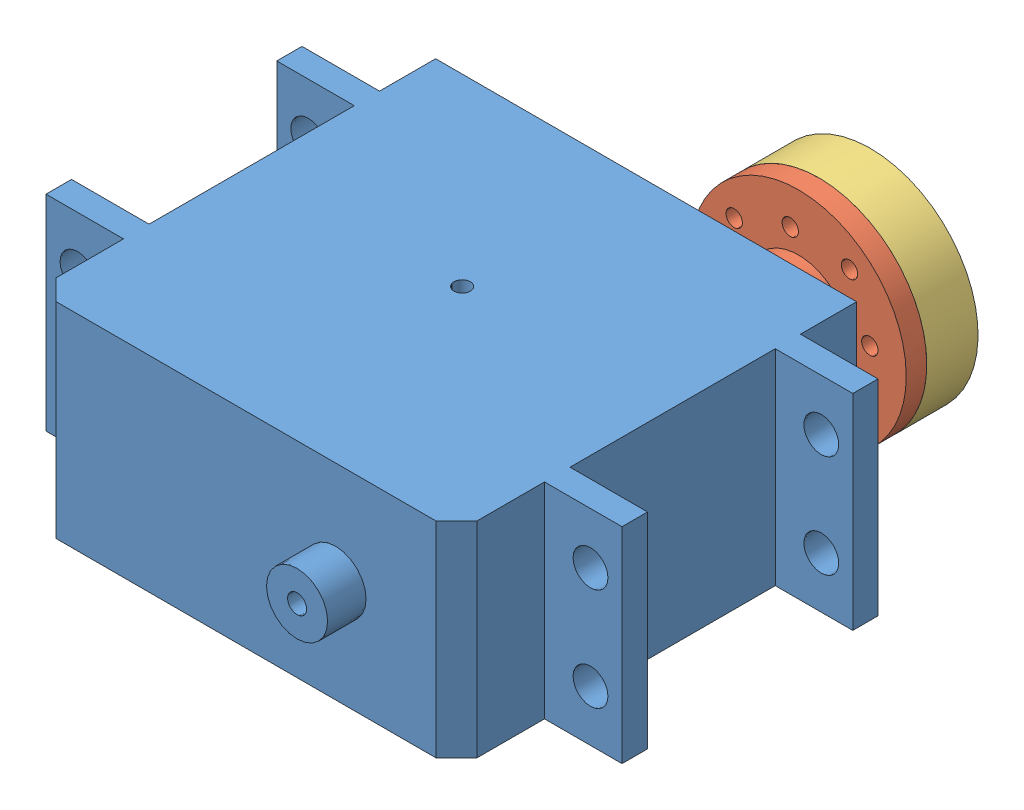
SolidWorks assembly Assem3-servo-with-horn, configuration Default. Lengths in mm.
Overall size (62.5 38.18 62.87).
4 component instances, 4 part files, 7 mates.
Components (placement in the parent):
- kondo-krs-2350-ics-asp-2012-02-16-1: kondo-krs-2350-ics-asp-2012-02-16 [Default] at (-0.0674 -11.2632 5.3988) size (62.5 30.72 48.12)
- horn-servo-puppy-1: horn-servo-puppy [Default] at (8.6626 -11.2632 -25.6512) x (0.621368 0.783519 0) z (-0.783519 0.621368 0) size (21 5 21)
- holder-ServoHorn-03052012-abs-3: holder-ServoHorn-03052012-abs [Default] at (8.6626 -11.2632 -30.6512) x (0.621368 0.783519 0) z (0 0 -1) size (24.45 21 5)
- al_d5_8p5-1: al_d5_8p5 [Default] at (3.6916 -17.5314 -30.6512) x (1 0 0) z (0 1 0) size (6 12 6)
Mates (geometry in assembly coordinates):
- Concentric9: concentric anti-aligned: cylinder of kondo-krs-2350-ics-asp-2012-02-16-1 through (8.6626 -11.2632 -87.3349) axis (0 0 1) radius 4; cylinder of horn-servo-puppy-1 through (8.6626 -11.2632 -30.6512) axis (0 0 -1) radius 5
- Distance20: distance = 1 mm anti-aligned: plane of horn-servo-puppy-1 through (8.6626 -11.2632 -25.6512) normal (0 0 1); plane of kondo-krs-2350-ics-asp-2012-02-16-1 through (8.6626 -11.2632 -24.6512) normal (0 0 -1)
- Concentric18: concentric aligned: cylinder of horn-servo-puppy-1 through (8.6626 -11.2632 -30.6512) axis (0 0 -1) radius 10.5; cylinder of holder-ServoHorn-03052012-abs-3 through (8.6626 -11.2632 -30.6512) axis (0 0 -1) radius 4
- Coincident4: coincident anti-aligned: plane of horn-servo-puppy-1 through (2.1382 -19.4902 -30.6512) normal (0 0 -1); plane of holder-ServoHorn-03052012-abs-3 through (8.6626 -11.2632 -30.6512) normal (0 0 1)
- Coaxiale1: concentric anti-aligned: cylinder of holder-ServoHorn-03052012-abs-3 through (3.6916 -17.5314 -13.8221) axis (0 0 -1) radius 2.95; cylinder of al_d5_8p5-1 through (3.6916 -17.5314 -30.6512) axis (0 0 1) radius 3
- Coïncidente1: coincident aligned: plane of holder-ServoHorn-03052012-abs-3 through (8.6626 -11.2632 -30.6512) normal (0 0 1); plane of al_d5_8p5-1 through (3.6916 -17.5314 -30.6512) normal (0 0 1)
- Concentric19: concentric aligned: cylinder of horn-servo-puppy-1 through (2.3944 -6.2923 -30.6512) axis (0 0 -1) radius 0.8; cylinder of holder-ServoHorn-03052012-abs-3 through (2.3944 -6.2923 -35.6512) axis (0 0 -1) radius 1.2
